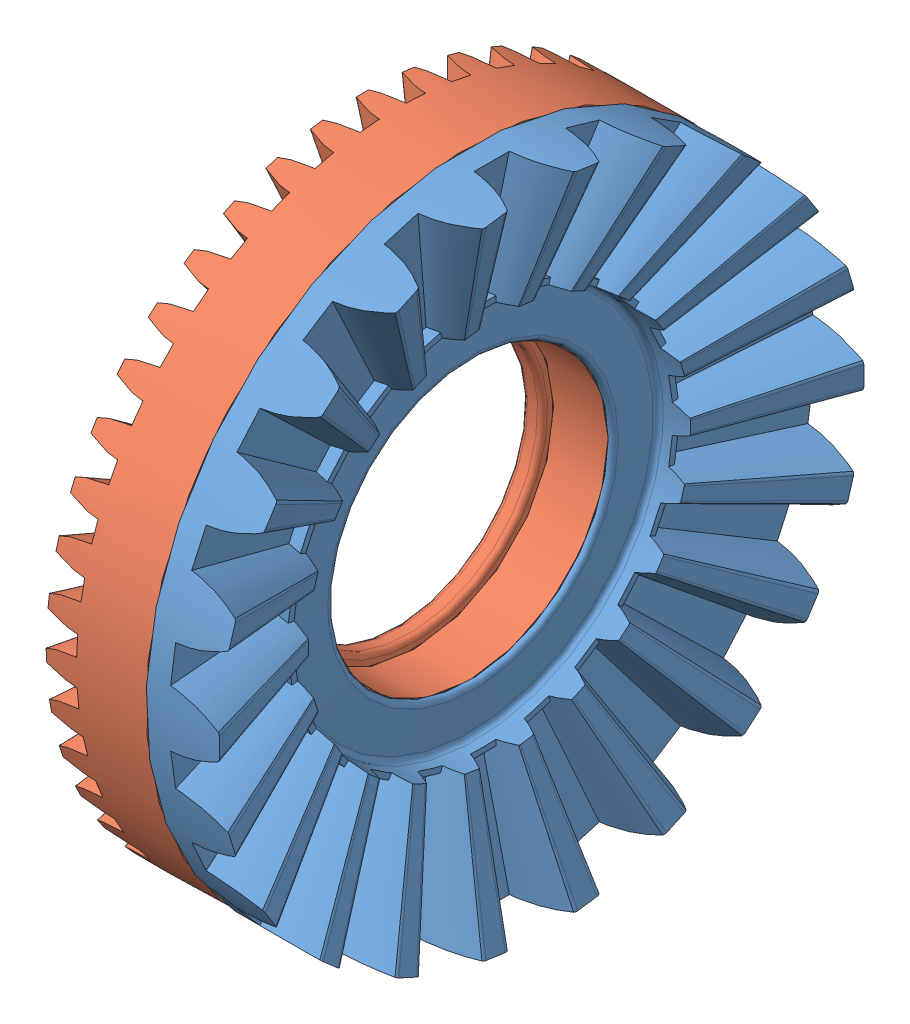
SolidWorks assembly precsGear240912, configuration По умолчанию. Lengths in mm.
Overall size (2148.06 197.59 275.44).
2 component instances, 2 part files, 10 mates.
Components (placement in the parent):
- gear2_240912-1: gear2_240912 [По умолчанию] at origin size (2042.38 68.15 183.13)
- my_gear3_240912-1: my_gear3_240912 [По умолчанию] at (8.5 0 0) x (-1 0 0) z (0 0.812003 -0.583653) size (404.7 85.78 181.68)
Mates (geometry in assembly coordinates):
- Концентричный1: concentric anti-aligned: cylinder of my_gear2_47-1 through (7.7082 0 0) axis (1 0 0) radius 14.1; cylinder of my_gear2_51-1 through (-10.1246 0 0) axis (-1 0 0) radius 10
- Совпадение1: coincident anti-aligned: plane of my_gear2_47-1 through (0 33.5724 0) normal (-1 0 0); plane of my_gear2_51-1 through (0 28.6516 -20.5815) normal (1 0 0)
- Концентричный2: concentric aligned: cylinder of my_gear2_51-1 through (-10.1246 0 0) axis (-1 0 0) radius 10; cylinder of road-1 through (7.1068 0 0) axis (-1 0 0) radius 10
- Совпадение2: coincident aligned: circle of my_gear2_51-1; plane of road-1 through (-2.8932 0 0) normal (-1 0 0)
- Совпадение3: coincident: plane of my_gear2_47-1 through (0 33.5724 0) normal (-1 0 0); plane of my_gear2_51a-1 through (0 9.4915 18.2074) normal (1 0 0)
- Концентричный5: concentric aligned: cylinder of my_gear2_47-1 through (7.7082 0 0) axis (-1 0 0) radius 14.1; cylinder of road-1 through (7.1068 0 0) axis (-1 0 0) radius 10
- Совпадение4: coincident aligned: circle of road-1; cylinder of my_gear3_240912-1 through (0.7918 0 0) axis (1 0 0) radius 14.1
- Концентричный6: concentric: cylinder of my_gear2_47-1 through (7.7082 0 0) axis (-1 0 0) radius 14.1; cylinder of my_gear2_51a-1 through (-1.2082 0 0) axis (-1 0 0) radius 14.1
- Совпадение5: coincident: plane of gear2_240912-1 through (7 78.5196 -39.75) normal (-1 0 0); plane of my_gear2_51a-1 through (5 19.3748 26.9551) normal (1 0 0)
- Совпадение6: coincident anti-aligned: plane of gear2_240912-1 through (7 78.5196 -39.75) normal (-1 0 0); plane of my_gear3_240912-1 through (7 -4.6914 63.7203) normal (1 0 0)
